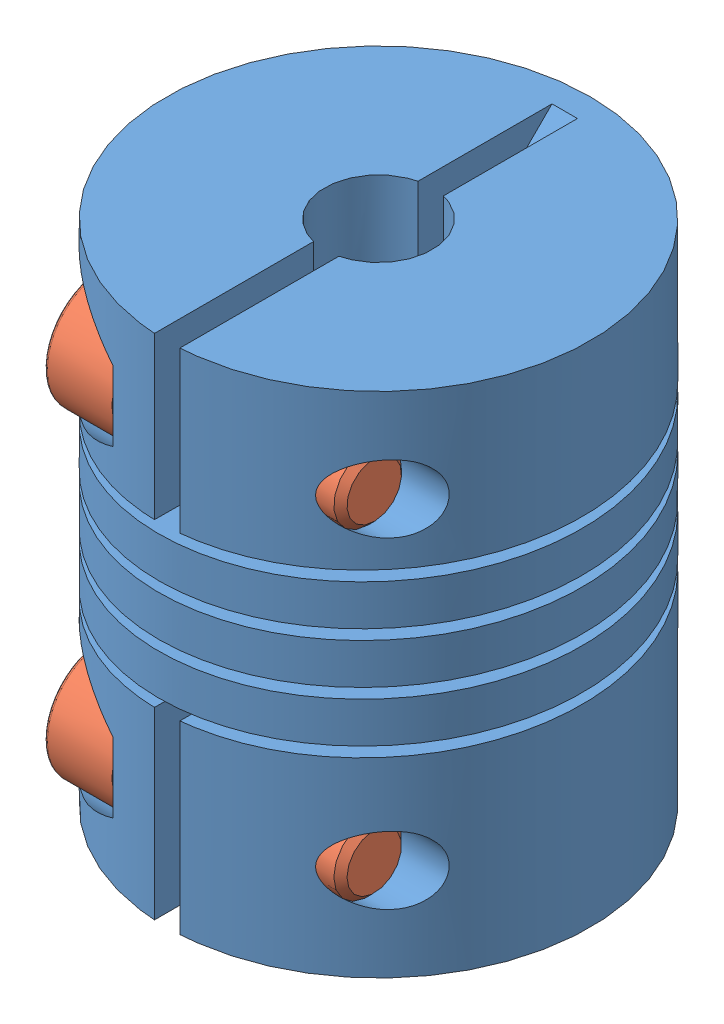
SolidWorks assembly Copler_screw_6.35mm_8mm, configuration Défaut. Lengths in mm.
Overall size (25 30 26.29).
5 component instances, 3 part files, 8 mates.
Components (placement in the parent):
- Copler_6.35mm_8mm-1: Copler_6.35mm_8mm [Défaut] at (-24.8723 -3.1988 0) size (25 30 26.29)
- ISO 4762 M4 x 12 - 12NN-1: ISO 4762 M4 x 12 - 12NN [ISO 4762 M4 x 12 - 12N] at (-32.6223 21.3012 8.5) x (1 0 0) z (0 -0.924225 -0.381849) size (16 7 7)
- ISO 4762 M4 x 12 - 12NN-2: ISO 4762 M4 x 12 - 12NN [ISO 4762 M4 x 12 - 12N] at (-32.6223 2.3012 8.5) size (16 7 7)
- ISO 4026 - M3 x 8-NN-1: ISO 4026 - M3 x 8-NN [ISO 4026 - M3 x 8-N] at (-37.3723 21.3012 0) size (8 3 3)
- ISO 4026 - M3 x 8-NN-2: ISO 4026 - M3 x 8-NN [ISO 4026 - M3 x 8-N] at (-37.3723 2.3012 0) size (8 3 3)
Mates (geometry in assembly coordinates):
- Coaxiale1: concentric aligned: cylinder of Copler_6.35mm_8mm-1 through (-4.8723 21.3012 8.5) axis (-1 0 0) radius 2; cylinder of ISO 4762 M4 x 12 - 12N-1 through (-64.3723 21.3012 8.5) axis (-1 0 0) radius 2
- Coïncidente1: coincident anti-aligned: plane of Copler_6.35mm_8mm-1 through (-28.6223 21.3012 8.5) normal (-1 0 0); plane of ISO 4762 M4 x 12 - 12N-1 through (-28.6223 19.9647 11.7348) normal (1 0 0)
- Coaxiale2: concentric aligned: cylinder of Copler_6.35mm_8mm-1 through (-4.8723 2.3012 8.5) axis (-1 0 0) radius 2; cylinder of ISO 4762 M4 x 12 - 12N-2 through (-64.3723 2.3012 8.5) axis (-1 0 0) radius 2
- Coïncidente2: coincident anti-aligned: plane of Copler_6.35mm_8mm-1 through (-28.6223 2.3012 8.5) normal (-1 0 0); plane of ISO 4762 M4 x 12 - 12N-2 through (-28.6223 5.8012 8.5) normal (1 0 0)
- Coaxiale3: concentric anti-aligned: cylinder of Copler_6.35mm_8mm-1 through (-44.8723 21.3012 0) axis (1 0 0) radius 1.5; cylinder of ISO 4026 - M3 x 8-N-1 through (-50.0723 21.3012 0) axis (-1 0 0) radius 1.5
- Tangent1: tangent aligned: cylinder of Copler_6.35mm_8mm-1 through (-24.8723 26.8012 0) axis (0 -1 0) radius 12.5; plane of ISO 4026 - M3 x 8-N-1 through (-37.3723 21.3012 0) normal (-1 0 0)
- Coaxiale4: concentric anti-aligned: cylinder of Copler_6.35mm_8mm-1 through (-44.8723 2.3012 0) axis (1 0 0) radius 1.5; cylinder of ISO 4026 - M3 x 8-N-2 through (-50.0723 2.3012 0) axis (-1 0 0) radius 1.5
- Tangent2: tangent aligned: cylinder of Copler_6.35mm_8mm-1 through (-24.8723 26.8012 0) axis (0 -1 0) radius 12.5; plane of ISO 4026 - M3 x 8-N-2 through (-37.3723 2.3012 0) normal (-1 0 0)
